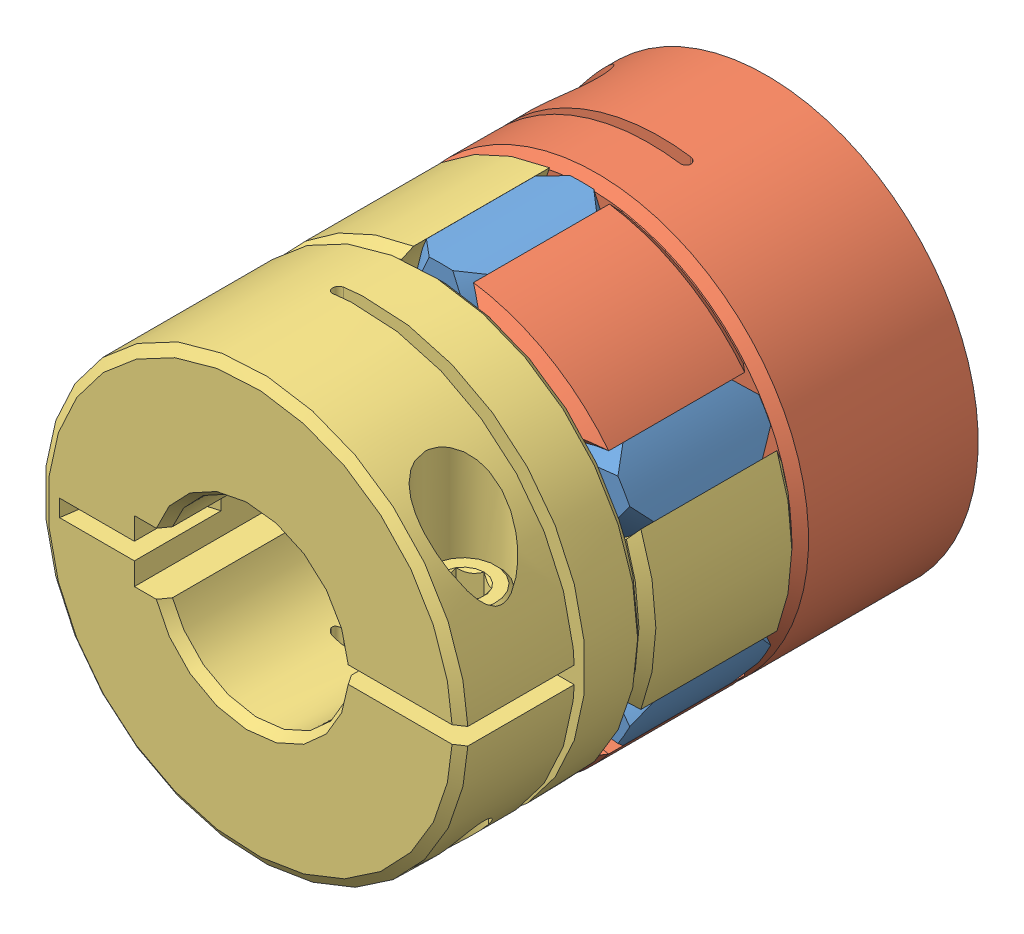
SolidWorks assembly Assem1, configuration Default. Lengths in mm.
Overall size (41.3 42.02 51.03).
3 component instances, 3 part files, 6 mates.
Components (placement in the parent):
- 9845T210_VIBRATE-DAMPING PRECISION FLEXIBLE SHAFT CPLG-1: 9845T210_VIBRATE-DAMPING PRECISION FLEXIBLE SHAFT CPLG [9845T21] at (14.3644 23.4902 31.8678) size (38.38 42 16.93)
- 9845T469_VIBRATE-DAMPING PRECISION FLEXIBLE SHAFT COUPLING-1: 9845T469_VIBRATE-DAMPING PRECISION FLEXIBLE SHAFT COUPLING [9845T469] at (14.3644 23.4902 25.3411) size (41.3 41.3 33.46)
- 9845T471_VIBRATE-DAMPING PRECISION FLEXIBLE SHAFT COUPLING-1: 9845T471_VIBRATE-DAMPING PRECISION FLEXIBLE SHAFT COUPLING [9845T471] at (14.3644 23.4902 23.3678) x (-1 0 0) z (0 0 -1) size (41.3 41.3 33.46)
Mates (geometry in assembly coordinates):
- Concentric1: concentric aligned: cylinder of 9845T469_VIBRATE-DAMPING PRECISION FLEXIBLE SHAFT COUPLING-1 through (14.3644 23.4902 44.0951) axis (0 0 -1) radius 7.5; cylinder of 9845T471_VIBRATE-DAMPING PRECISION FLEXIBLE SHAFT COUPLING-1 through (14.3644 23.4902 49.8678) axis (0 0 -1) radius 9
- Concentric2: concentric aligned: cone of 9845T210_VIBRATE-DAMPING PRECISION FLEXIBLE SHAFT CPLG-1 through (14.3644 23.4902 27.7347) axis (0 0 -1); cylinder of 9845T469_VIBRATE-DAMPING PRECISION FLEXIBLE SHAFT COUPLING-1 through (14.3644 23.4902 44.0951) axis (0 0 -1) radius 7.5
- Coincident1: coincident aligned: plane of 9845T210_VIBRATE-DAMPING PRECISION FLEXIBLE SHAFT CPLG-1 through (14.3644 23.4902 31.8678) normal (0 1 0); plane of 9845T469_VIBRATE-DAMPING PRECISION FLEXIBLE SHAFT COUPLING-1 through (14.3644 23.4902 25.5951) normal (0 1 0)
- Coincident2: coincident anti-aligned: plane of 9845T210_VIBRATE-DAMPING PRECISION FLEXIBLE SHAFT CPLG-1 through (14.3644 23.4902 16.8411) normal (0 0 -1); plane of 9845T469_VIBRATE-DAMPING PRECISION FLEXIBLE SHAFT COUPLING-1 through (14.3644 23.4902 16.8411) normal (0 0 1)
- Coincident3: coincident anti-aligned: plane of 9845T210_VIBRATE-DAMPING PRECISION FLEXIBLE SHAFT CPLG-1 through (14.3644 23.4902 31.8678) normal (1 0 0); plane of 9845T471_VIBRATE-DAMPING PRECISION FLEXIBLE SHAFT COUPLING-1 through (14.3644 23.4902 23.3678) normal (-1 0 0)
- Coincident5: coincident anti-aligned: plane of 9845T210_VIBRATE-DAMPING PRECISION FLEXIBLE SHAFT CPLG-1 through (14.3644 23.4902 31.8678) normal (0 0 1); plane of 9845T471_VIBRATE-DAMPING PRECISION FLEXIBLE SHAFT COUPLING-1 through (14.3644 23.4902 31.8678) normal (0 0 -1)
